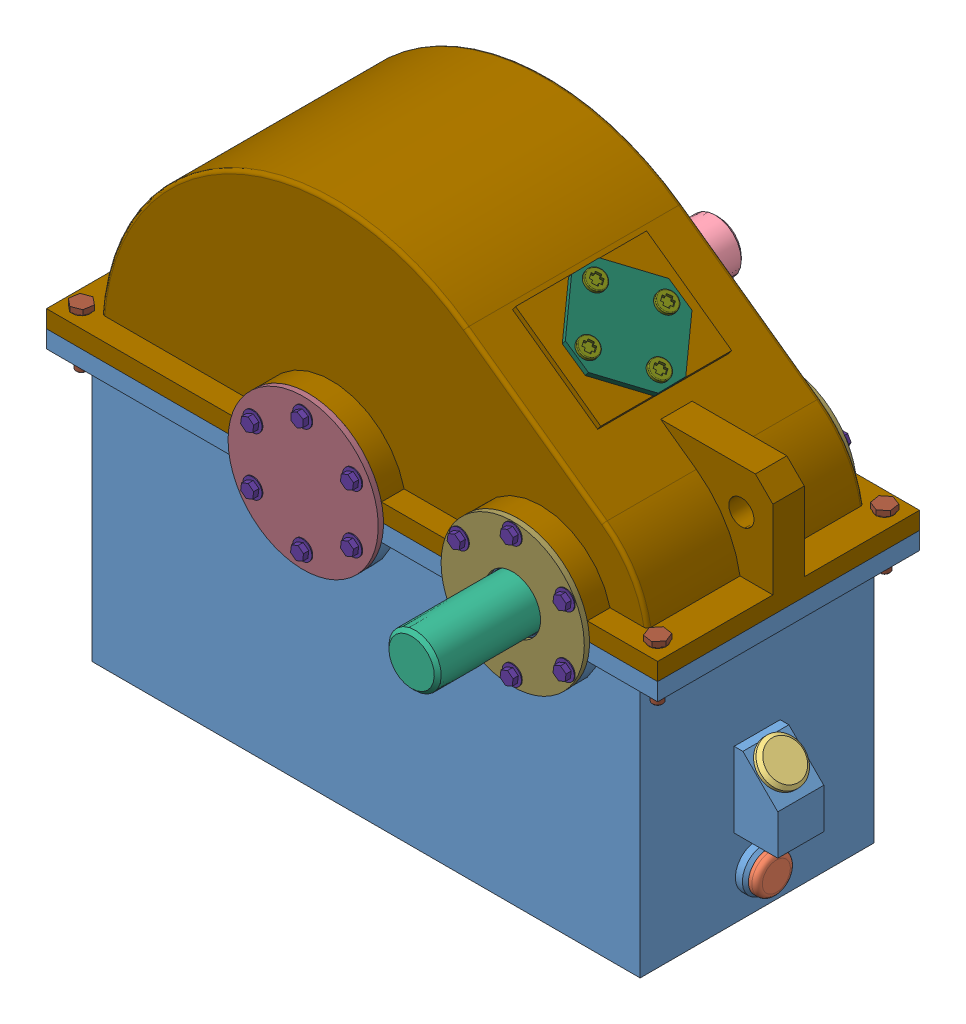
SolidWorks assembly Final assembly, configuration Default. Lengths in mm.
Overall size (358.46 292 295.81).
51 component instances, 17 part files, 101 mates.
Components (placement in the parent):
- housing-1: housing [Default] at (163.2462 83.2819 271.9967) size (357 160 150)
- oil plug-1: oil plug [Default] at (286.2462 105.7819 271.9967) x (0 -0.9057 0.42392) z (1 0 0) size (22 22 45)
- oil scale-1: oil scale [Default] at (336.3246 165.8603 271.9967) x (0.136836 -0.136836 -0.981097) z (-0.707107 -0.707107 0) size (25 25 34)
- high speed shaft-1: high speed shaft [Default] at (138.2462 243.2819 112.0846) x (0 0 -1) z (-0.866883 0.498512 0) size (230 36 36)
- key 2-1: key 2 [Default] at (118.7413 254.4984 280.0846) x (0 0 -1) z (0.866883 -0.498512 0) size (50 14 9)
- low speed shaft-1: low speed shaft [Default] at (258.2462 243.2819 192.8924) x (0 0 1) z (0.465815 -0.884882 0) size (215 32 32)
- key 1-1: key 1 [Default] at (267.0967 226.4691 247.8924) x (0 0 1) z (-0.465815 0.884882 0) size (50 10 6)
- spur gear_gb-1: spur gear_gb [GB - Spur gear 2M 93T 20PA 60FW ---S93A75H50L0.8N] at (138.389 242.9082 236.1459) x (0 0 1) z (-0.934117 -0.356968 0) size (60 189.97 189.99)
- spur gear_gb-2: spur gear_gb [GB - Spur gear 2M 26T 20PA 62FW ---S26A75H50L0.8N] at (258.6002 243.4682 233.1663) x (0 0 1) z (0.884882 0.465815 0) size (62 55.72 56)
- housing cover-1: housing cover [Default] at (138.2462 243.2819 271.9967) size (350 132 150)
- deep groove ball bearings gb-1: deep groove ball bearings gb [Rolling bearings 16006 GB 276-94] at (258.2462 243.2819 204.757) x (0 0 1) z (-0.993815 0.111049 0) size (9 55 55)
- deep groove ball bearings gb-2: deep groove ball bearings gb [Rolling bearings 16006 GB 276-94] at (258.2462 243.2819 343.2237) x (0 0 1) z (-0.994696 0.102858 0) size (9 55 55)
- deep groove ball bearings gb-3: deep groove ball bearings gb [Rolling bearings 16006 GB 276-94] at (138.2462 243.2819 202.9972) x (0 0 1) z (-0.974701 0.223514 0) size (9 55 55)
- deep groove ball bearings gb-4: deep groove ball bearings gb [Rolling bearings 16006 GB 276-94] at (138.2462 243.2819 338.147) x (0 0 1) z (-0.996313 0.085795 0) size (9 55 55)
- screw 1-1: screw 1 [Default] at (328.2462 223.2819 336.9967) x (-0.988664 0 -0.150147) z (0 1 0) size (11.55 10 33.5)
- screw 1-2: screw 1 [Default] at (328.2462 223.2819 206.9967) x (-0.932532 0 -0.361087) z (0 1 0) size (11.55 10 33.5)
- screw 1-3: screw 1 [Default] at (-1.7538 223.2819 206.9967) x (-0.780112 0 -0.625639) z (0 1 0) size (11.55 10 33.5)
- screw 1-4: screw 1 [Default] at (-1.7538 223.2819 336.9967) x (0.15821 0 -0.987405) z (0 1 0) size (11.55 10 33.5)
- bearing cover 1-1: bearing cover 1 [Default] at (258.2462 243.2819 346.9967) size (82 82 3)
- bearing cover 1-2: bearing cover 1 [Default] at (258.2462 243.2819 193.9967) size (82 82 3)
- bearing cover 3-1: bearing cover 3 [Default] at (138.2462 243.2819 346.9967) size (86 86 3)
- bearing cover 2-1: bearing cover 2 [Default] at (138.2462 243.2819 193.9967) size (86 86 3)
- check panel-1: check panel [Default] at (245.8987 335.8695 271.2307) x (0.011615 -0.008341 0.999898) z (-0.583333 -0.812233 0) size (60 60 3)
- screw 3-1: screw 3 [Default] at (222.687 342.6904 272.1355) x (0.665255 -0.477776 -0.57373) z (0.583333 0.812233 0) size (11 11 10)
- screw 3-2: screw 3 [Default] at (240.9635 329.5645 249.6343) x (0.659722 -0.473803 -0.583333) z (0.583333 0.812233 0) size (11 11 10)
- screw 3-3: screw 3 [Default] at (240.9627 329.565 294.635) x (0.663114 -0.476239 -0.577474) z (0.583333 0.812233 0) size (11 11 10)
- screw 3-4: screw 3 [Default] at (259.2388 316.4395 272.1343) x (0.659722 -0.473803 -0.583333) z (0.583333 0.812233 0) size (11 11 10)
- screw 2-1: screw 2 [Default] at (138.2462 276.2819 349.9967) x (-0.85701 -0.515299 0) z (0 0 -1) size (11 11 11.5)
- screw 2-2: screw 2 [Default] at (109.6674 259.7819 349.9967) x (-0.923728 -0.383049 0) z (0 0 -1) size (11 11 11.5)
- screw 2-3: screw 2 [Default] at (109.6674 226.7819 349.9967) x (-0.923728 -0.383049 0) z (0 0 -1) size (11 11 11.5)
- screw 2-4: screw 2 [Default] at (138.2462 210.2819 349.9967) x (-0.923728 -0.383049 0) z (0 0 -1) size (11 11 11.5)
- screw 2-5: screw 2 [Default] at (166.8251 226.7819 349.9967) x (-0.923728 -0.383049 0) z (0 0 -1) size (11 11 11.5)
- screw 2-6: screw 2 [Default] at (166.8251 259.7819 349.9967) x (-0.923728 -0.383049 0) z (0 0 -1) size (11 11 11.5)
- screw 2-7: screw 2 [Default] at (258.2462 278.2819 349.9967) x (-0.923728 -0.383049 0) z (0 0 -1) size (11 11 11.5)
- screw 2-8: screw 2 [Default] at (288.5571 260.7819 349.9967) x (-0.923728 -0.383049 0) z (0 0 -1) size (11 11 11.5)
- screw 2-9: screw 2 [Default] at (288.5571 225.7819 349.9967) x (-0.923728 -0.383049 0) z (0 0 -1) size (11 11 11.5)
- screw 2-10: screw 2 [Default] at (258.2462 208.2819 349.9967) x (-0.923728 -0.383049 0) z (0 0 -1) size (11 11 11.5)
- screw 2-11: screw 2 [Default] at (227.9353 225.7819 349.9967) x (-0.923728 -0.383049 0) z (0 0 -1) size (11 11 11.5)
- screw 2-12: screw 2 [Default] at (227.9353 260.7819 349.9967) x (-0.923728 -0.383049 0) z (0 0 -1) size (11 11 11.5)
- screw 2-13: screw 2 [Default] at (258.2462 278.2819 193.9967) size (11 11 11.5)
- screw 2-14: screw 2 [Default] at (288.5571 260.7819 193.9967) size (11 11 11.5)
- screw 2-15: screw 2 [Default] at (288.5571 225.7819 193.9967) size (11 11 11.5)
- screw 2-16: screw 2 [Default] at (258.2462 208.2819 193.9967) size (11 11 11.5)
- screw 2-17: screw 2 [Default] at (227.9353 225.7819 193.9967) x (0.97201 0.234941 0) z (0 0 1) size (11 11 11.5)
- screw 2-18: screw 2 [Default] at (227.9353 260.7819 193.9967) x (0.997934 -0.06424 0) z (0 0 1) size (11 11 11.5)
- screw 2-19: screw 2 [Default] at (138.2462 276.2819 193.9967) x (0.331426 0.943481 0) z (0 0 1) size (11 11 11.5)
- screw 2-20: screw 2 [Default] at (166.8251 259.7819 193.9967) x (0.302609 0.953115 0) z (0 0 1) size (11 11 11.5)
- screw 2-21: screw 2 [Default] at (109.6674 259.7819 193.9967) x (0.68284 0.730568 0) z (0 0 1) size (11 11 11.5)
- screw 2-22: screw 2 [Default] at (109.6674 226.7819 193.9967) x (0.994896 -0.10091 0) z (0 0 1) size (11 11 11.5)
- screw 2-23: screw 2 [Default] at (138.2462 210.2819 193.9967) x (0.506009 0.862528 0) z (0 0 1) size (11 11 11.5)
- screw 2-24: screw 2 [Default] at (166.8251 226.7819 193.9967) x (0.971404 0.237433 0) z (0 0 1) size (11 11 11.5)
Mates (geometry in assembly coordinates):
- Concentric1: concentric aligned: circle of housing-1; cylinder of oil plug-1 through (326.2462 105.7819 271.9967) axis (-1 0 0) radius 8.5
- Coincident1: coincident anti-aligned: plane of housing-1 through (326.2462 105.7819 271.9967) normal (1 0 0); plane of oil plug-1 through (326.2462 105.7819 271.9967) normal (-1 0 0)
- Concentric2: concentric aligned: cylinder of housing-1 through (298.1409 127.6765 271.9967) axis (0.707107 0.707107 0) radius 7.5; cylinder of oil scale-1 through (312.283 141.8186 271.9967) axis (0.707107 0.707107 0) radius 7
- Coincident2: coincident anti-aligned: plane of housing-1 through (325.2462 171.2819 346.9977) normal (0.707107 0.707107 0); plane of oil scale-1 through (333.4962 163.0319 271.9967) normal (-0.707107 -0.707107 0)
- Coincident3: coincident anti-aligned: plane of high speed shaft-1 through (126.5433 250.0118 244.0846) normal (-0.866883 0.498512 0); plane of key 2-1 through (126.5433 250.0118 280.0846) normal (0.866883 -0.498512 0)
- Concentric3: concentric aligned: cylinder of high speed shaft-1 through (126.5433 250.0118 280.0846) axis (-0.866883 0.498512 0) radius 7; cylinder of key 2-1 through (126.5433 250.0118 280.0846) axis (-0.866883 0.498512 0) radius 7
- Concentric4: concentric aligned: cylinder of high speed shaft-1 through (126.5433 250.0118 244.0846) axis (-0.866883 0.498512 0) radius 7; cylinder of key 2-1 through (126.5433 250.0118 244.0846) axis (-0.866883 0.498512 0) radius 7
- Concentric5: concentric aligned: cylinder of housing-1 through (138.2462 243.2819 196.9967) axis (0 0 1) radius 27.5; cylinder of high speed shaft-1 through (138.2462 243.2819 232.0846) axis (0 0 1) radius 18
- Coincident4: coincident anti-aligned: plane of low speed shaft-1 through (264.3018 231.7784 287.8924) normal (0.465815 -0.884882 0); plane of key 1-1 through (264.3018 231.7784 247.8924) normal (-0.465815 0.884882 0)
- Concentric6: concentric aligned: cylinder of low speed shaft-1 through (264.3018 231.7784 247.8924) axis (0.465815 -0.884882 0) radius 5; cylinder of key 1-1 through (264.3018 231.7784 247.8924) axis (0.465815 -0.884882 0) radius 5
- Concentric7: concentric aligned: cylinder of low speed shaft-1 through (264.3018 231.7784 287.8924) axis (0.465815 -0.884882 0) radius 5; cylinder of key 1-1 through (264.3018 231.7784 287.8924) axis (0.465815 -0.884882 0) radius 5
- Concentric8: concentric anti-aligned: cylinder of housing-1 through (258.2462 243.2819 196.9967) axis (0 0 1) radius 27.5; cylinder of low speed shaft-1 through (258.2462 243.2819 296.8924) axis (0 0 -1) radius 16
- Concentric9: concentric aligned: cylinder of high speed shaft-1 through (138.2462 243.2819 232.0846) axis (0 0 1) radius 18; cylinder of low speed gear-1 through (138.2462 243.2819 236.1459) axis (0 0 1) radius 18
- Parallel1: parallel: plane of key 2-1 through (130.0329 256.0799 280.0846) normal (0.498512 0.866883 0); plane of low speed gear-1 through (123.6756 261.8007 236.1459) normal (0.934117 0.356968 0)
- Concentric10: concentric anti-aligned: cylinder of low speed shaft-1 through (258.2462 243.2819 296.8924) axis (0 0 -1) radius 16; cylinder of high speed gear-1 through (258.2462 243.2819 233.1663) axis (0 0 1) radius 16
- Parallel2: parallel aligned: plane of key 1-1 through (259.8774 229.4493 247.8924) normal (-0.884882 -0.465815 0); plane of high speed gear-1 through (271.8751 228.9845 233.1663) normal (-0.884882 -0.465815 0)
- GearMate1: gear = 52 : 186 mm: circle of low speed gear-1; circle of high speed gear-1
- Concentric15: concentric anti-aligned: cylinder of housing-1 through (258.2462 243.2819 196.9967) axis (0 0 1) radius 27.5; cylinder of deep groove ball bearings gb-1 through (258.2462 243.2819 196.0463) axis (0 0 -1) radius 27.5
- Concentric16: concentric anti-aligned: cylinder of housing-1 through (258.2462 243.2819 196.9967) axis (0 0 1) radius 27.5; cylinder of deep groove ball bearings gb-2 through (258.2462 243.2819 334.513) axis (0 0 -1) radius 27.5
- Concentric17: concentric anti-aligned: cylinder of housing-1 through (138.2462 243.2819 196.9967) axis (0 0 1) radius 27.5; cylinder of deep groove ball bearings gb-3 through (138.2462 243.2819 194.2865) axis (0 0 -1) radius 27.5
- Concentric18: concentric anti-aligned: cylinder of housing-1 through (138.2462 243.2819 196.9967) axis (0 0 1) radius 27.5; cylinder of deep groove ball bearings gb-4 through (138.2462 243.2819 329.4363) axis (0 0 -1) radius 27.5
- Coincident11: coincident aligned: plane of housing-1 through (338.2462 233.2819 346.9967) normal (0 0 1); plane of housing cover-1 through (-11.7538 253.2819 346.9967) normal (0 0 1)
- Coincident12: coincident aligned: plane of housing-1 through (-11.7538 233.2819 346.9967) normal (-1 0 0); plane of housing cover-1 through (-11.7538 253.2819 196.9967) normal (-1 0 0)
- Concentric19: concentric aligned: cylinder of housing cover-1 through (328.2462 375.2819 336.9967) axis (0 -1 0) radius 4; cylinder of screw 1-1 through (328.2462 253.2819 336.9967) axis (0 -1 0) radius 3
- Coincident13: coincident anti-aligned: plane of housing cover-1 through (138.2462 253.2819 271.9967) normal (0 1 0); plane of screw 1-1 through (328.2462 253.2819 336.9967) normal (0 -1 0)
- Concentric20: concentric aligned: cylinder of housing cover-1 through (328.2462 375.2819 206.9967) axis (0 -1 0) radius 4; cylinder of screw 1-2 through (328.2462 253.2819 206.9967) axis (0 -1 0) radius 3
- Coincident14: coincident anti-aligned: plane of housing-1 through (163.2462 243.2819 271.9967) normal (0 1 0); plane of housing cover-1 through (6.2462 243.2819 333.9967) normal (0 -1 0)
- Coincident15: coincident anti-aligned: plane of housing cover-1 through (138.2462 253.2819 271.9967) normal (0 1 0); plane of screw 1-2 through (328.2462 253.2819 206.9967) normal (0 -1 0)
- Concentric21: concentric aligned: cylinder of housing cover-1 through (-1.7538 375.2819 206.9967) axis (0 -1 0) radius 4; cylinder of screw 1-3 through (-1.7538 253.2819 206.9967) axis (0 -1 0) radius 3
- Coincident16: coincident anti-aligned: plane of housing cover-1 through (138.2462 253.2819 271.9967) normal (0 1 0); plane of screw 1-3 through (-1.7538 253.2819 206.9967) normal (0 -1 0)
- Concentric22: concentric aligned: cylinder of housing cover-1 through (-1.7538 375.2819 336.9967) axis (0 -1 0) radius 4; cylinder of screw 1-4 through (-1.7538 253.2819 336.9967) axis (0 -1 0) radius 3
- Coincident17: coincident anti-aligned: plane of housing cover-1 through (138.2462 253.2819 271.9967) normal (0 1 0); plane of screw 1-4 through (-1.7538 253.2819 336.9967) normal (0 -1 0)
- Concentric23: concentric anti-aligned: cylinder of housing cover-1 through (258.2462 278.2819 346.9967) axis (0 0 1) radius 2.5; cylinder of bearing cover 1-1 through (258.2462 278.2819 349.9967) axis (0 0 -1) radius 3
- Concentric24: concentric anti-aligned: cylinder of housing cover-1 through (258.2462 243.2819 196.9967) axis (0 0 1) radius 41; cylinder of bearing cover 1-1 through (258.2462 243.2819 349.9967) axis (0 0 -1) radius 41
- Concentric25: concentric anti-aligned: cylinder of housing cover-1 through (258.2462 278.2819 346.9967) axis (0 0 1) radius 2.5; cylinder of bearing cover 1-2 through (258.2462 278.2819 196.9967) axis (0 0 -1) radius 3
- Concentric26: concentric anti-aligned: cylinder of housing cover-1 through (258.2462 243.2819 196.9967) axis (0 0 1) radius 41; cylinder of bearing cover 1-2 through (258.2462 243.2819 196.9967) axis (0 0 -1) radius 41
- Concentric27: concentric anti-aligned: cylinder of housing cover-1 through (138.2462 243.2819 196.9967) axis (0 0 1) radius 43; cylinder of bearing cover 3-1 through (138.2462 243.2819 349.9967) axis (0 0 -1) radius 43
- Concentric28: concentric anti-aligned: cylinder of housing cover-1 through (166.8251 259.7819 346.9967) axis (0 0 1) radius 2.5; cylinder of bearing cover 3-1 through (166.8251 259.7819 349.9967) axis (0 0 -1) radius 3
- Concentric29: concentric anti-aligned: cylinder of housing cover-1 through (138.2462 276.2819 346.9967) axis (0 0 1) radius 2.5; cylinder of bearing cover 2-1 through (138.2462 276.2819 196.9967) axis (0 0 -1) radius 3
- Concentric30: concentric anti-aligned: cylinder of housing cover-1 through (138.2462 243.2819 196.9967) axis (0 0 1) radius 43; cylinder of bearing cover 2-1 through (138.2462 243.2819 196.9967) axis (0 0 -1) radius 43
- Coincident19: coincident anti-aligned: plane of housing cover-1 through (216.9962 352.9333 271.9967) normal (0.583333 0.812233 0); plane of check panel-1 through (244.1487 333.4328 271.2307) normal (-0.583333 -0.812233 0)
- Concentric32: concentric aligned: cylinder of housing cover-1 through (95.733 166.0865 271.9967) axis (0.583333 0.812233 0) radius 4; cylinder of check panel-1 through (225.5247 346.8083 271.9967) axis (0.583333 0.812233 0) radius 4
- Concentric33: concentric anti-aligned: cylinder of housing cover-1 through (95.733 166.0865 271.9967) axis (0.583333 0.812233 0) radius 4; cylinder of screw 3-1 through (227.2747 349.245 271.9967) axis (-0.583333 -0.812233 0) radius 4
- Coincident20: coincident anti-aligned: plane of check panel-1 through (245.8987 335.8695 271.2307) normal (0.583333 0.812233 0); plane of screw 3-1 through (227.3536 349.1883 272.1355) normal (-0.583333 -0.812233 0)
- Concentric34: concentric anti-aligned: cylinder of housing cover-1 through (114.0082 152.9615 249.4967) axis (0.583333 0.812233 0) radius 4; cylinder of screw 3-2 through (245.5499 336.12 249.4967) axis (-0.583333 -0.812233 0) radius 4
- Coincident21: coincident anti-aligned: plane of check panel-1 through (245.8987 335.8695 271.2307) normal (0.583333 0.812233 0); plane of screw 3-2 through (245.6302 336.0623 249.6343) normal (-0.583333 -0.812233 0)
- Concentric35: concentric anti-aligned: cylinder of housing cover-1 through (114.0082 152.9615 294.4967) axis (0.583333 0.812233 0) radius 4; cylinder of screw 3-3 through (245.5499 336.12 294.4967) axis (-0.583333 -0.812233 0) radius 4
- Coincident22: coincident anti-aligned: plane of check panel-1 through (245.8987 335.8695 271.2307) normal (0.583333 0.812233 0); plane of screw 3-3 through (245.6294 336.0629 294.635) normal (-0.583333 -0.812233 0)
- Concentric36: concentric anti-aligned: cylinder of housing cover-1 through (132.2835 139.8365 271.9967) axis (0.583333 0.812233 0) radius 4; cylinder of screw 3-4 through (263.8251 322.995 271.9967) axis (-0.583333 -0.812233 0) radius 4
- Coincident23: coincident anti-aligned: plane of check panel-1 through (245.8987 335.8695 271.2307) normal (0.583333 0.812233 0); plane of screw 3-4 through (263.9054 322.9373 272.1343) normal (-0.583333 -0.812233 0)
- Concentric37: concentric anti-aligned: cylinder of bearing cover 3-1 through (138.2462 276.2819 349.9967) axis (0 0 -1) radius 3; cylinder of screw 2-1 through (138.2462 276.2819 341.9967) axis (0 0 1) radius 2.5
- Concentric38: concentric anti-aligned: cylinder of bearing cover 3-1 through (109.6674 259.7819 349.9967) axis (0 0 -1) radius 3; cylinder of screw 2-2 through (109.6674 259.7819 341.9967) axis (0 0 1) radius 2.5
- Concentric39: concentric anti-aligned: cylinder of bearing cover 3-1 through (109.6674 226.7819 349.9967) axis (0 0 -1) radius 3; cylinder of screw 2-3 through (109.6674 226.7819 341.9967) axis (0 0 1) radius 2.5
- Concentric40: concentric anti-aligned: cylinder of bearing cover 3-1 through (138.2462 210.2819 349.9967) axis (0 0 -1) radius 3; cylinder of screw 2-4 through (138.2462 210.2819 341.9967) axis (0 0 1) radius 2.5
- Concentric41: concentric anti-aligned: cylinder of bearing cover 3-1 through (166.8251 226.7819 349.9967) axis (0 0 -1) radius 3; cylinder of screw 2-5 through (166.8251 226.7819 341.9967) axis (0 0 1) radius 2.5
- Concentric42: concentric anti-aligned: cylinder of bearing cover 3-1 through (166.8251 259.7819 349.9967) axis (0 0 -1) radius 3; cylinder of screw 2-6 through (166.8251 259.7819 341.9967) axis (0 0 1) radius 2.5
- Concentric43: concentric anti-aligned: cylinder of bearing cover 1-1 through (258.2462 278.2819 349.9967) axis (0 0 -1) radius 3; cylinder of screw 2-7 through (258.2462 278.2819 341.9967) axis (0 0 1) radius 2.5
- Concentric44: concentric anti-aligned: cylinder of bearing cover 1-1 through (288.5571 260.7819 349.9967) axis (0 0 -1) radius 3; cylinder of screw 2-8 through (288.5571 260.7819 341.9967) axis (0 0 1) radius 2.5
- Concentric45: concentric anti-aligned: cylinder of bearing cover 1-1 through (288.5571 225.7819 349.9967) axis (0 0 -1) radius 3; cylinder of screw 2-9 through (288.5571 225.7819 341.9967) axis (0 0 1) radius 2.5
- Concentric46: concentric aligned: cylinder of housing-1 through (258.2462 208.2819 346.9967) axis (0 0 1) radius 2.5; cylinder of screw 2-10 through (258.2462 208.2819 341.9967) axis (0 0 1) radius 2.5
- Concentric47: concentric aligned: cylinder of housing-1 through (227.9353 225.7819 346.9967) axis (0 0 1) radius 2.5; cylinder of screw 2-11 through (227.9353 225.7819 341.9967) axis (0 0 1) radius 2.5
- Concentric48: concentric aligned: cylinder of housing cover-1 through (227.9353 260.7819 346.9967) axis (0 0 1) radius 2.5; cylinder of screw 2-12 through (227.9353 260.7819 341.9967) axis (0 0 1) radius 2.5
- Coincident25: coincident anti-aligned: plane of bearing cover 3-1 through (138.2462 243.2819 349.9967) normal (0 0 1); plane of screw 2-2 through (109.6674 259.7819 349.9967) normal (0 0 -1)
- Coincident26: coincident anti-aligned: plane of bearing cover 3-1 through (138.2462 243.2819 349.9967) normal (0 0 1); plane of screw 2-3 through (109.6674 226.7819 349.9967) normal (0 0 -1)
- Coincident27: coincident anti-aligned: plane of bearing cover 3-1 through (138.2462 243.2819 349.9967) normal (0 0 1); plane of screw 2-4 through (138.2462 210.2819 349.9967) normal (0 0 -1)
- Coincident28: coincident anti-aligned: plane of bearing cover 3-1 through (138.2462 243.2819 349.9967) normal (0 0 1); plane of screw 2-5 through (166.8251 226.7819 349.9967) normal (0 0 -1)
- Coincident29: coincident anti-aligned: plane of bearing cover 3-1 through (138.2462 243.2819 349.9967) normal (0 0 1); plane of screw 2-6 through (166.8251 259.7819 349.9967) normal (0 0 -1)
- Coincident30: coincident anti-aligned: plane of bearing cover 1-1 through (258.2462 243.2819 349.9967) normal (0 0 1); plane of screw 2-11 through (227.9353 225.7819 349.9967) normal (0 0 -1)
- Coincident31: coincident anti-aligned: plane of bearing cover 1-1 through (258.2462 243.2819 349.9967) normal (0 0 1); plane of screw 2-12 through (227.9353 260.7819 349.9967) normal (0 0 -1)
- Coincident32: coincident anti-aligned: plane of bearing cover 1-1 through (258.2462 243.2819 349.9967) normal (0 0 1); plane of screw 2-7 through (258.2462 278.2819 349.9967) normal (0 0 -1)
- Coincident33: coincident anti-aligned: plane of bearing cover 1-1 through (258.2462 243.2819 349.9967) normal (0 0 1); plane of screw 2-8 through (288.5571 260.7819 349.9967) normal (0 0 -1)
- Coincident34: coincident anti-aligned: plane of housing cover-1 through (-11.7538 253.2819 346.9967) normal (0 0 1); plane of bearing cover 1-1 through (258.2462 243.2819 346.9967) normal (0 0 -1)
- Coincident35: coincident anti-aligned: plane of bearing cover 1-1 through (258.2462 243.2819 349.9967) normal (0 0 1); plane of screw 2-9 through (288.5571 225.7819 349.9967) normal (0 0 -1)
- Coincident36: coincident anti-aligned: plane of bearing cover 1-1 through (258.2462 243.2819 349.9967) normal (0 0 1); plane of screw 2-10 through (258.2462 208.2819 349.9967) normal (0 0 -1)
- Coincident37: coincident anti-aligned: plane of housing cover-1 through (-11.7538 253.2819 346.9967) normal (0 0 1); plane of bearing cover 3-1 through (138.2462 243.2819 346.9967) normal (0 0 -1)
- Coincident38: coincident anti-aligned: plane of housing-1 through (338.2462 233.2819 196.9967) normal (0 0 -1); plane of bearing cover 1-2 through (258.2462 243.2819 196.9967) normal (0 0 1)
- Coincident39: coincident anti-aligned: plane of housing cover-1 through (-11.7538 253.2819 196.9967) normal (0 0 -1); plane of bearing cover 2-1 through (138.2462 243.2819 196.9967) normal (0 0 1)
- Concentric49: concentric aligned: cylinder of bearing cover 1-2 through (258.2462 278.2819 196.9967) axis (0 0 -1) radius 3; cylinder of screw 2-13 through (258.2462 278.2819 201.9967) axis (0 0 -1) radius 2.5
- Concentric50: concentric aligned: cylinder of bearing cover 1-2 through (288.5571 260.7819 196.9967) axis (0 0 -1) radius 3; cylinder of screw 2-14 through (288.5571 260.7819 201.9967) axis (0 0 -1) radius 2.5
- Concentric51: concentric aligned: cylinder of bearing cover 1-2 through (288.5571 225.7819 196.9967) axis (0 0 -1) radius 3; cylinder of screw 2-15 through (288.5571 225.7819 201.9967) axis (0 0 -1) radius 2.5
- Concentric52: concentric aligned: cylinder of bearing cover 1-2 through (258.2462 208.2819 196.9967) axis (0 0 -1) radius 3; cylinder of screw 2-16 through (258.2462 208.2819 201.9967) axis (0 0 -1) radius 2.5
- Concentric53: concentric aligned: cylinder of bearing cover 1-2 through (227.9353 225.7819 196.9967) axis (0 0 -1) radius 3; cylinder of screw 2-17 through (227.9353 225.7819 201.9967) axis (0 0 -1) radius 2.5
- Concentric54: concentric aligned: cylinder of bearing cover 1-2 through (227.9353 260.7819 196.9967) axis (0 0 -1) radius 3; cylinder of screw 2-18 through (227.9353 260.7819 201.9967) axis (0 0 -1) radius 2.5
- Concentric55: concentric aligned: cylinder of bearing cover 2-1 through (138.2462 276.2819 196.9967) axis (0 0 -1) radius 3; circle of screw 2-19
- Coincident40: coincident anti-aligned: plane of bearing cover 3-1 through (138.2462 243.2819 349.9967) normal (0 0 1); plane of screw 2-1 through (138.2462 276.2819 349.9967) normal (0 0 -1)
- Concentric56: concentric aligned: cylinder of bearing cover 2-1 through (166.8251 259.7819 196.9967) axis (0 0 -1) radius 3; cylinder of screw 2-20 through (166.8251 259.7819 201.9967) axis (0 0 -1) radius 2.5
- Concentric57: concentric aligned: cylinder of bearing cover 2-1 through (109.6674 259.7819 196.9967) axis (0 0 -1) radius 3; cylinder of screw 2-21 through (109.6674 259.7819 201.9967) axis (0 0 -1) radius 2.5
- Concentric58: concentric aligned: cylinder of bearing cover 2-1 through (109.6674 226.7819 196.9967) axis (0 0 -1) radius 3; cylinder of screw 2-22 through (109.6674 226.7819 201.9967) axis (0 0 -1) radius 2.5
- Concentric59: concentric aligned: cylinder of bearing cover 2-1 through (138.2462 210.2819 196.9967) axis (0 0 -1) radius 3; cylinder of screw 2-23 through (138.2462 210.2819 201.9967) axis (0 0 -1) radius 2.5
- Concentric60: concentric aligned: cylinder of bearing cover 2-1 through (166.8251 226.7819 196.9967) axis (0 0 -1) radius 3; cylinder of screw 2-24 through (166.8251 226.7819 201.9967) axis (0 0 -1) radius 2.5
- Coincident41: coincident anti-aligned: plane of bearing cover 1-2 through (258.2462 243.2819 193.9967) normal (0 0 -1); plane of screw 2-13 through (258.2462 278.2819 193.9967) normal (0 0 1)
- Coincident43: coincident anti-aligned: plane of bearing cover 1-2 through (258.2462 243.2819 193.9967) normal (0 0 -1); plane of screw 2-15 through (288.5571 225.7819 193.9967) normal (0 0 1)
- Coincident44: coincident anti-aligned: plane of bearing cover 1-2 through (258.2462 243.2819 193.9967) normal (0 0 -1); plane of screw 2-16 through (258.2462 208.2819 193.9967) normal (0 0 1)
- Coincident45: coincident anti-aligned: plane of bearing cover 2-1 through (138.2462 243.2819 193.9967) normal (0 0 -1); plane of screw 2-23 through (138.2462 210.2819 193.9967) normal (0 0 1)
- Coincident46: coincident anti-aligned: plane of bearing cover 1-2 through (258.2462 243.2819 193.9967) normal (0 0 -1); plane of screw 2-17 through (227.9353 225.7819 193.9967) normal (0 0 1)
- Coincident47: coincident anti-aligned: plane of bearing cover 1-2 through (258.2462 243.2819 193.9967) normal (0 0 -1); plane of screw 2-18 through (227.9353 260.7819 193.9967) normal (0 0 1)
- Coincident48: coincident anti-aligned: plane of bearing cover 2-1 through (138.2462 243.2819 193.9967) normal (0 0 -1); plane of screw 2-20 through (166.8251 259.7819 193.9967) normal (0 0 1)
- Coincident49: coincident anti-aligned: plane of bearing cover 2-1 through (138.2462 243.2819 193.9967) normal (0 0 -1); plane of screw 2-24 through (166.8251 226.7819 193.9967) normal (0 0 1)
- Coincident50: coincident anti-aligned: plane of bearing cover 2-1 through (138.2462 243.2819 193.9967) normal (0 0 -1); plane of screw 2-19 through (138.2462 276.2819 193.9967) normal (0 0 1)
- Coincident51: coincident anti-aligned: plane of bearing cover 2-1 through (138.2462 243.2819 193.9967) normal (0 0 -1); plane of screw 2-21 through (109.6674 259.7819 193.9967) normal (0 0 1)
- Coincident52: coincident anti-aligned: plane of bearing cover 2-1 through (138.2462 243.2819 193.9967) normal (0 0 -1); plane of screw 2-22 through (109.6674 226.7819 193.9967) normal (0 0 1)
